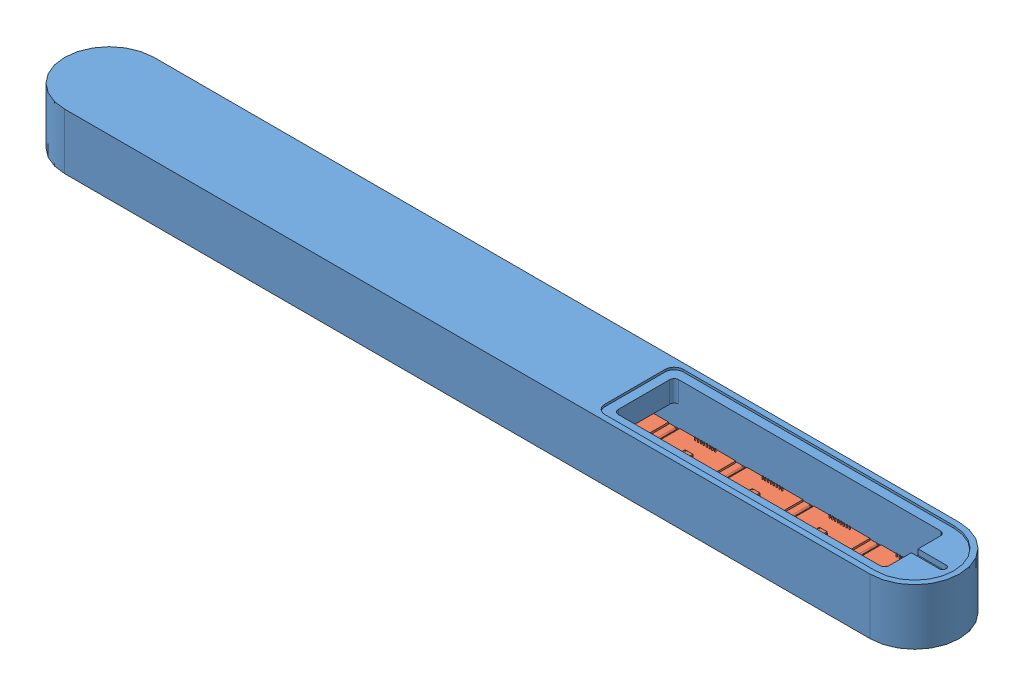
SolidWorks assembly assembly, configuration Default. Lengths in mm.
Overall size (800 50 80).
15 component instances, 4 part files, 9 mates.
Components (placement in the parent):
- flipclock-1: flipclock [Default] at (360.5261 406.6613 667.8991) size (800 50 80)
- plexi-1: plexi [Default] at (360.5261 407.6613 667.8991) x (1 0 0) z (0 0 1) size (789 3 69) (hidden)
- hatsotakaro-1: hatsotakaro [Default] at (360.5261 454.6613 667.8991) x (1 0 0) z (0 0 1) size (283 1.5 68) (hidden)
- MAX7219_8X8LED_BOARD-14: MAX7219_8X8LED_BOARD [Default] at (715.5262 417.6613 692.8992) x (-1 0 0) z (0 -1 0) size (66.4 60.5 11.27)
- MAX7219_8X8LED_BOARD-15: MAX7219_8X8LED_BOARD [Default] at (655.5262 417.6613 692.8992) x (-1 0 0) z (0 -1 0) size (66.4 60.5 11.27)
- MAX7219_8X8LED_BOARD-16: MAX7219_8X8LED_BOARD [Default] at (595.5262 417.6613 692.8992) x (-1 0 0) z (0 -1 0) size (66.4 60.5 11.27)
- MAX7219_8X8LED_BOARD-17: MAX7219_8X8LED_BOARD [Default] at (535.5262 417.6613 692.8992) x (-1 0 0) z (0 -1 0) size (66.4 60.5 11.27)
- MAX7219_8X8LED_BOARD-18: MAX7219_8X8LED_BOARD [Default] at (475.5262 417.6613 692.8992) x (-1 0 0) z (0 -1 0) size (66.4 60.5 11.27)
- MAX7219_8X8LED_BOARD-19: MAX7219_8X8LED_BOARD [Default] at (415.5262 417.6613 692.8992) x (-1 0 0) z (0 -1 0) size (66.4 60.5 11.27)
- MAX7219_8X8LED_BOARD-20: MAX7219_8X8LED_BOARD [Default] at (355.5262 417.6613 692.8992) x (-1 0 0) z (0 -1 0) size (66.4 60.5 11.27)
- MAX7219_8X8LED_BOARD-21: MAX7219_8X8LED_BOARD [Default] at (295.5262 417.6613 692.8992) x (-1 0 0) z (0 -1 0) size (66.4 60.5 11.27)
- MAX7219_8X8LED_BOARD-22: MAX7219_8X8LED_BOARD [Default] at (235.5262 417.6613 692.8992) x (-1 0 0) z (0 -1 0) size (66.4 60.5 11.27)
- MAX7219_8X8LED_BOARD-23: MAX7219_8X8LED_BOARD [Default] at (175.5262 417.6613 692.8992) x (-1 0 0) z (0 -1 0) size (66.4 60.5 11.27)
- MAX7219_8X8LED_BOARD-24: MAX7219_8X8LED_BOARD [Default] at (115.5262 417.6613 692.8992) x (-1 0 0) z (0 -1 0) size (66.4 60.5 11.27)
- MAX7219_8X8LED_BOARD-25: MAX7219_8X8LED_BOARD [Default] at (55.5262 417.6613 692.8992) x (-1 0 0) z (0 -1 0) size (66.4 60.5 11.27)
Mates (geometry in assembly coordinates):
- Coincident6: coincident anti-aligned: plane of flipclock-1 through (0.5261 410.6613 667.8991) normal (0 -1 0); plane of plexi-1 through (720.5261 410.6613 667.8991) normal (0 1 0)
- Concentric1: concentric aligned: circle of flipclock-1; cylinder of plexi-1 through (720.5261 410.6613 667.8991) axis (0 -1 0) radius 34.5
- Coincident10: coincident anti-aligned: plane of flipclock-1 through (478.5261 454.6613 640.8991) normal (0 1 0); plane of hatsotakaro-1 through (720.5261 454.6613 667.8991) normal (0 -1 0)
- Width1: width anti-aligned: plane of hatsotakaro-1 through (720.5261 456.1613 633.8991) normal (0 0 -1); plane of hatsotakaro-1 through (478.5261 456.1613 701.8991) normal (0 0 1); plane of flipclock-1 through (720.5261 454.6613 632.8991) normal (0 0 1); plane of flipclock-1 through (478.5261 454.6613 702.8991) normal (0 0 -1)
- Concentric2: concentric anti-aligned: cylinder of flipclock-1 through (720.5261 454.6613 667.8991) axis (0 1 0) radius 35; cylinder of hatsotakaro-1 through (720.5261 456.1613 667.8991) axis (0 -1 0) radius 34
- Concentric4: concentric anti-aligned: circle of flipclock-1; circle of plexi-1
- Coincident15: coincident aligned: plane of flipclock-1 through (0.5261 410.6613 667.8991) normal (0 -1 0); plane of MAX7219_8X8LED_BOARD-14 through (690.5261 410.6613 667.8991) normal (0 -1 0)
- Coincident12: coincident anti-aligned: plane of flipclock-1 through (360.5261 416.6613 637.8991) normal (0 0 1); plane of MAX7219_8X8LED_BOARD-14 through (720.5261 410.6613 637.8991) normal (0 0 -1)
- Coincident14: coincident anti-aligned: plane of flipclock-1 through (720.5261 434.6613 644.8991) normal (-1 0 0); plane of MAX7219_8X8LED_BOARD-14 through (720.5261 410.6613 697.8991) normal (1 0 0)
